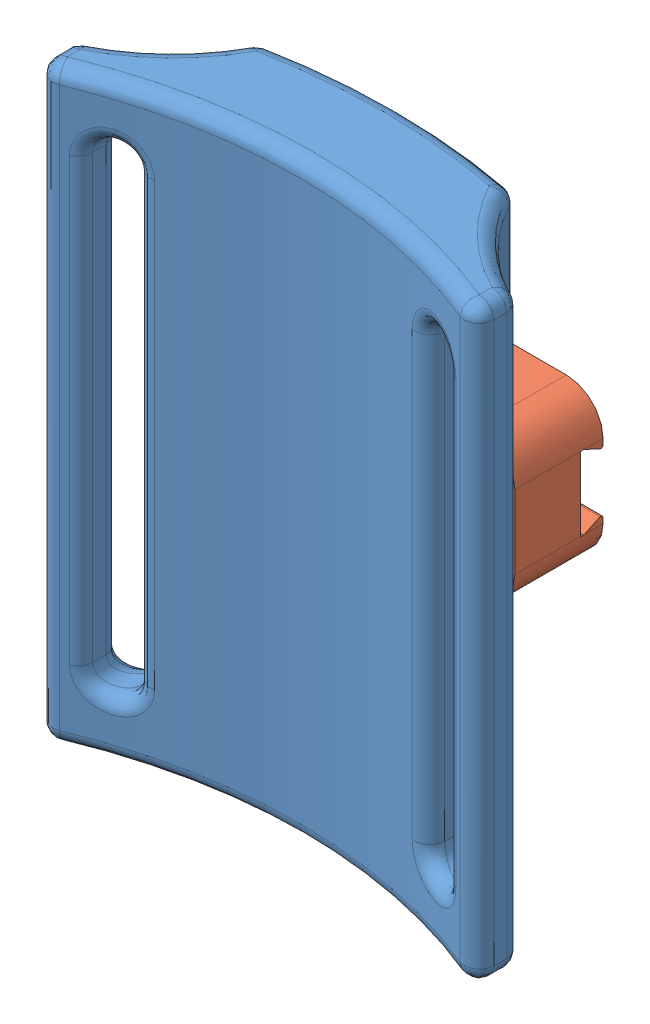
SolidWorks assembly sliding_mechanism, configuration Default. Lengths in mm.
Overall size (60 80 31.83).
2 component instances, 2 part files, 1 mates.
Components (placement in the parent):
- slide1-2: slide1 [Default] at (35.9132 -9.9128 77.9746) size (60 80 19.04)
- slide2_centered-2: slide2_centered [Default] at (35.9132 26.7329 3.1866) x (-1 0 0) z (0 0 -1) size (30 20 23)
Mates (geometry in assembly coordinates):
- Distance1: distance = 1 mm anti-aligned: plane of slide1-2 through (24.9132 0.0872 4.1866) normal (0 0 -1); plane of slide2_centered-2 through (35.9132 26.7329 3.1866) normal (0 0 1)
